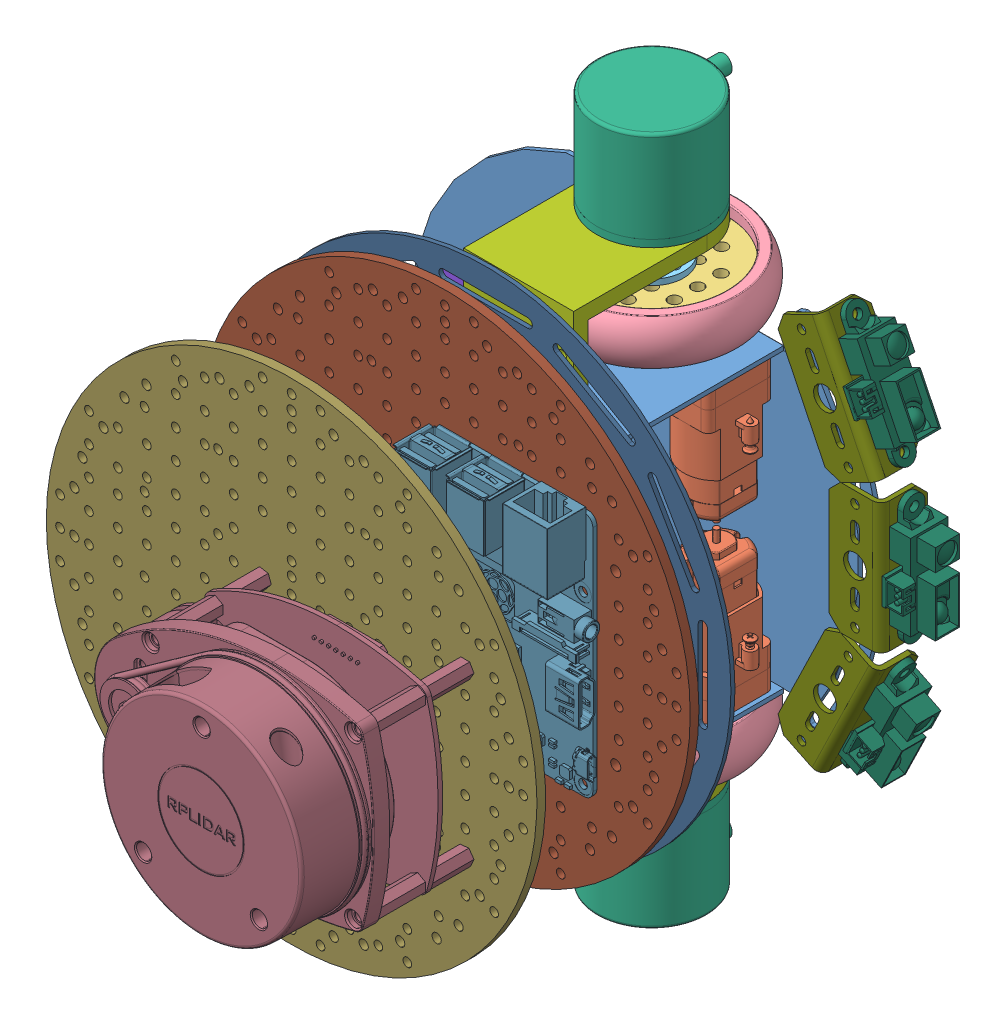
SolidWorks assembly ABOT, configuration По умолчанию. Lengths in mm.
Overall size (177.2 238 222.07).
28 component instances, 16 part files, 67 mates.
Components (placement in the parent):
- LOWER_PLATE-1: LOWER_PLATE [По умолчанию] x (0 1 0) z (1 0 0) size (144.85 55.5 162.2)
- TT_ANGLE_MOTOR_PART-1: TT_ANGLE_MOTOR_PART [По умолчанию] at (11.0834 -43.5 12.4406) x (-1 0 0) z (0 1 0) size (47.1 23 58.3)
- TT_ANGLE_MOTOR_PART-2: TT_ANGLE_MOTOR_PART [По умолчанию] at (11.0834 43.5 16.5594) x (-1 0 0) z (0 -1 0) size (47.1 23 58.3)
- MBOT_WHEEL-2: MBOT_WHEEL [Default] at (0 64 14.5) x (-0.008283 0 0.999966) z (0 -1 0) size (63.9 63.9 19.9)
  - TIMING_PULLEY_90T-1: TIMING_PULLEY_90T [Default] at origin size (57.7 57.7 16)
  - SLICK_TYRE_64x16-1: SLICK_TYRE_64x16 [Default] x (0 0 -1) z (1 0 0) size (15.8 63.9 63.9)
- MBOT_WHEEL-3: MBOT_WHEEL [Default] at (0 -64 14.5) x (0.824889 0 -0.565294) z (0 1 0) size (63.9 63.9 19.9)
  - TIMING_PULLEY_90T-1: TIMING_PULLEY_90T [Default] at origin size (57.7 57.7 16)
  - SLICK_TYRE_64x16-1: SLICK_TYRE_64x16 [Default] x (0 0 -1) z (1 0 0) size (15.8 63.9 63.9)
- 6MM_SHAFT_FLANGE-1: 6MM_SHAFT_FLANGE [Default] at (0 68 14.5) x (-0.701226 0 -0.712939) z (0 1 0) size (22 22 12)
- 6MM_SHAFT_FLANGE-2: 6MM_SHAFT_FLANGE [Default] at (0 -68 14.5) x (0.983008 0 0.183562) z (0 -1 0) size (22 22 12)
- ENCODER_LPD3806-360BM-G5-24C-1: ENCODER_LPD3806-360BM-G5-24C [Default] at (0 -119 14.5) x (-1 0 0) z (0 0 -1) size (38 51 44.01)
- PRINT_ENCODER_MOUNT-1: PRINT_ENCODER_MOUNT [По умолчанию] at (0 -85 14.5) x (0 1 0) z (1 0 0) size (46.5 65 65)
- ENCODER_LPD3806-360BM-G5-24C-2: ENCODER_LPD3806-360BM-G5-24C [Default] at (0 119 14.5) x (1 0 0) z (0 0 -1) size (38 51 44.01)
- PRINT_ENCODER_MOUNT-2: PRINT_ENCODER_MOUNT [По умолчанию] at (0 85 14.5) x (0 -1 0) z (-1 0 0) size (46.5 65 65)
- CASTER_WHEEL_CASE-1: CASTER_WHEEL_CASE [Default] at (-78 0 -10.45) x (0 1 0) z (1 0 0) size (48.4 15.95 32.2)
- CASTER_WHEEL_BALL-1: CASTER_WHEEL_BALL [Default] at (-78 0 -10.45) x (0 1 0) z (1 0 0) size (14 14 14)
- UPPER_PLATE-1: UPPER_PLATE [Default] at (-10 0 60.5) x (-1 0 0) z (0 0 1) size (169.5 169.5 1.4)
- CUT_PLEX_PLATE_0-1: CUT_PLEX_PLATE_0 [Default] at (-10 0 72.95) x (-1 0 0) z (0 0 1) size (169.5 169.5 3)
- CUT_PLEX_PLATE_1-1: CUT_PLEX_PLATE_1 [По умолчанию] at (-10 0 125.95) size (169.5 169.5 3)
- LIDAR_AXIS_FRAME-1: LIDAR_AXIS_FRAME [По умолчанию] at (22 0 183.15) size (97.49 71.78 63.21)
- RPI3-1: RPI3 [По умолчанию] at (-3.5 -31.5 86.35) size (58.5 87.6 19.8)
- GP2Y0A41SK0F_AXIS_FRAME-1: GP2Y0A41SK0F_AXIS_FRAME [По умолчанию] at (81.2 0 -6.5) x (0 -1 0) z (0 0 1) size (44.5 13.5 18.9)
- SHARP_IR_MOUNTING_BRACKET-1: SHARP_IR_MOUNTING_BRACKET [Default] at (67.7 0 3) x (-1 0 0) z (0 -1 0) size (18 16 45)
- GP2Y0A41SK0F_AXIS_FRAME-4: GP2Y0A41SK0F_AXIS_FRAME [По умолчанию] at (68.5722 54.7695 -6.5) x (0.43785 -0.899048 0) z (0 0 1) size (44.5 13.5 18.9)
- SHARP_IR_MOUNTING_BRACKET-4: SHARP_IR_MOUNTING_BRACKET [Default] at (56.435 48.8585 3) x (-0.899048 -0.43785 0) z (0.43785 -0.899048 0) size (18 16 45)
- SHARP_IR_MOUNTING_BRACKET-5: SHARP_IR_MOUNTING_BRACKET [Default] at (56.435 -48.8585 3) x (-0.899048 0.43785 0) z (-0.43785 -0.899048 0) size (18 16 45)
- GP2Y0A41SK0F_AXIS_FRAME-5: GP2Y0A41SK0F_AXIS_FRAME [По умолчанию] at (68.5722 -54.7695 -6.5) x (-0.43785 -0.899048 0) z (0 0 1) size (44.5 13.5 18.9)
Mates (geometry in assembly coordinates):
- Концентричный1: concentric aligned: cylinder of LOWER_PLATE-1 through (0 54 14.5) axis (0 -1 0) radius 4; cylinder of TT_ANGLE_MOTOR_PART-2 through (0 59.3 14.5) axis (0 -1 0) radius 2.7
- Параллельность1: parallel anti-aligned: plane of LOWER_PLATE-1 through (0 0 1.5) normal (0 0 1); plane of TT_ANGLE_MOTOR_PART-2 through (28.5 50.5 3) normal (0 0 -1)
- Совпадение2: coincident anti-aligned: plane of LOWER_PLATE-1 through (-32.5 50.5 55) normal (0 -1 0); plane of TT_ANGLE_MOTOR_PART-2 through (-8.5 50.5 5.5) normal (0 1 0)
- Концентричный2: concentric anti-aligned: cylinder of LOWER_PLATE-1 through (0 54 14.5) axis (0 -1 0) radius 4; cylinder of TT_ANGLE_MOTOR_PART-1 through (0 -59.3 14.5) axis (0 1 0) radius 2.7
- Параллельность2: parallel aligned: plane of LOWER_PLATE-1 through (0 0 1.5) normal (0 0 1); plane of TT_ANGLE_MOTOR_PART-1 through (28.5 -50.5 26) normal (0 0 1)
- Совпадение4: coincident anti-aligned: plane of LOWER_PLATE-1 through (-32.5 -50.5 55) normal (0 1 0); plane of TT_ANGLE_MOTOR_PART-1 through (-8.5 -50.5 23.5) normal (0 -1 0)
- Концентричный3: concentric anti-aligned: cylinder of TT_ANGLE_MOTOR_PART-2 through (0 59.3 14.5) axis (0 -1 0) radius 2.7; cylinder of MBOT_WHEEL-2/TIMING_PULLEY_90T-1 through (0 52 14.5) axis (0 1 0) radius 5
- Концентричный4: concentric anti-aligned: cylinder of TT_ANGLE_MOTOR_PART-1 through (0 -59.3 14.5) axis (0 1 0) radius 2.7; cylinder of MBOT_WHEEL-3/TIMING_PULLEY_90T-1 through (0 -52 14.5) axis (0 -1 0) radius 5
- Совпадение5: coincident anti-aligned: plane of LOWER_PLATE-1 through (0 -52 55) normal (0 -1 0); plane of MBOT_WHEEL-3/TIMING_PULLEY_90T-1 through (0 -52 14.5) normal (0 1 0)
- Совпадение6: coincident anti-aligned: plane of LOWER_PLATE-1 through (0 52 55) normal (0 1 0); plane of MBOT_WHEEL-2/TIMING_PULLEY_90T-1 through (0 52 14.5) normal (0 -1 0)
- Концентричный5: concentric anti-aligned: cylinder of MBOT_WHEEL-2/TIMING_PULLEY_90T-1 through (0 64 14.5) axis (0 1 0) radius 4; cylinder of 6MM_SHAFT_FLANGE-1 through (0 80 14.5) axis (0 -1 0) radius 3
- Концентричный6: concentric anti-aligned: cylinder of MBOT_WHEEL-2/TIMING_PULLEY_90T-1 through (0.0663 68 6.5003) axis (0 -1 0) radius 2.05; cylinder of 6MM_SHAFT_FLANGE-1 through (0.0663 60 6.5003) axis (0 1 0) radius 1.5
- Совпадение7: coincident anti-aligned: plane of MBOT_WHEEL-2/TIMING_PULLEY_90T-1 through (0 68 14.5) normal (0 1 0); plane of 6MM_SHAFT_FLANGE-1 through (0 68 14.5) normal (0 -1 0)
- Концентричный7: concentric anti-aligned: cylinder of MBOT_WHEEL-3/TIMING_PULLEY_90T-1 through (0 -64 14.5) axis (0 -1 0) radius 4; cylinder of 6MM_SHAFT_FLANGE-2 through (0 -80 14.5) axis (0 1 0) radius 3
- Концентричный10: concentric anti-aligned: cylinder of MBOT_WHEEL-3/TIMING_PULLEY_90T-1 through (6.5991 -68 9.9776) axis (0 1 0) radius 2.05; cylinder of 6MM_SHAFT_FLANGE-2 through (6.5991 -60 9.9776) axis (0 -1 0) radius 1.5
- Совпадение8: coincident anti-aligned: plane of MBOT_WHEEL-3/TIMING_PULLEY_90T-1 through (0 -68 14.5) normal (0 -1 0); plane of 6MM_SHAFT_FLANGE-2 through (0 -68 14.5) normal (0 1 0)
- Концентричный11: concentric anti-aligned: cylinder of ENCODER_LPD3806-360BM-G5-24C-1 through (0 -80 14.5) axis (0 -1 0) radius 10; cylinder of PRINT_ENCODER_MOUNT-1 through (0 -99 14.5) axis (0 1 0) radius 10
- Концентричный12: concentric aligned: cylinder of ENCODER_LPD3806-360BM-G5-24C-1 through (0 -92 28.5) axis (0 1 0) radius 1.5; cylinder of PRINT_ENCODER_MOUNT-1 through (0 -85 28.5) axis (0 1 0) radius 1.5
- Совпадение9: coincident anti-aligned: plane of ENCODER_LPD3806-360BM-G5-24C-1 through (0 -85 14.5) normal (0 1 0); plane of PRINT_ENCODER_MOUNT-1 through (-32.5 -85 14.5) normal (0 -1 0)
- Концентричный13: concentric anti-aligned: cylinder of 6MM_SHAFT_FLANGE-2 through (0 -80 14.5) axis (0 1 0) radius 3; cylinder of ENCODER_LPD3806-360BM-G5-24C-1 through (0 -68 14.5) axis (0 -1 0) radius 3
- Совпадение10: coincident anti-aligned: plane of 6MM_SHAFT_FLANGE-2 through (0 -80 14.5) normal (0 -1 0); plane of ENCODER_LPD3806-360BM-G5-24C-1 through (0 -80 14.5) normal (0 1 0)
- Параллельность4: parallel anti-aligned: plane of PRINT_ENCODER_MOUNT-1 through (-32.5 -85 55.5) normal (0 0 -1); plane of LOWER_PLATE-1 through (0 0 1.5) normal (0 0 1)
- Совпадение12: coincident anti-aligned: plane of ENCODER_LPD3806-360BM-G5-24C-2 through (0 85 14.5) normal (0 -1 0); plane of PRINT_ENCODER_MOUNT-2 through (32.5 85 14.5) normal (0 1 0)
- Концентричный14: concentric aligned: cylinder of ENCODER_LPD3806-360BM-G5-24C-2 through (0 92 28.5) axis (0 -1 0) radius 1.5; cylinder of PRINT_ENCODER_MOUNT-2 through (0 85 28.5) axis (0 -1 0) radius 1.5
- Концентричный15: concentric anti-aligned: cylinder of ENCODER_LPD3806-360BM-G5-24C-2 through (0 80 14.5) axis (0 1 0) radius 10; cylinder of PRINT_ENCODER_MOUNT-2 through (0 99 14.5) axis (0 -1 0) radius 10
- Концентричный16: concentric anti-aligned: cylinder of 6MM_SHAFT_FLANGE-1 through (0 80 14.5) axis (0 -1 0) radius 3; cylinder of ENCODER_LPD3806-360BM-G5-24C-2 through (0 68 14.5) axis (0 1 0) radius 3
- Параллельность5: parallel aligned: plane of PRINT_ENCODER_MOUNT-2 through (32.5 85 60.5) normal (0 0 1); plane of LOWER_PLATE-1 through (0 0 1.5) normal (0 0 1)
- Совпадение14: coincident anti-aligned: plane of 6MM_SHAFT_FLANGE-1 through (0 80 14.5) normal (0 1 0); plane of ENCODER_LPD3806-360BM-G5-24C-2 through (0 80 14.5) normal (0 -1 0)
- Концентричный17: concentric anti-aligned: cylinder of LOWER_PLATE-1 through (-78 0 1.5) axis (0 0 -1) radius 16; cylinder of CASTER_WHEEL_CASE-1 through (-78 0 -13.45) axis (0 0 1) radius 16.1
- Концентричный18: concentric aligned: cylinder of LOWER_PLATE-1 through (-78 20 0) axis (0 0 1) radius 2.05; cylinder of CASTER_WHEEL_CASE-1 through (-78 20 -13.45) axis (0 0 1) radius 2
- Совпадение15: coincident anti-aligned: plane of LOWER_PLATE-1 through (0 0 1.5) normal (0 0 1); plane of CASTER_WHEEL_CASE-1 through (-78 0 1.5) normal (0 0 -1)
- Совпадение16: coordinate: point of CASTER_WHEEL_CASE-1; point of CASTER_WHEEL_BALL-1
- Концентричный22: concentric aligned: cylinder of LOWER_PLATE-1 through (25 -45 55.5) axis (0 0 -1) radius 1.5; cylinder of UPPER_PLATE-1 through (25 -45 61.9) axis (0 0 -1) radius 2
- Концентричный23: concentric aligned: cylinder of LOWER_PLATE-1 through (-25 45 55.5) axis (0 0 -1) radius 1.5; cylinder of UPPER_PLATE-1 through (-25 45 61.9) axis (0 0 -1) radius 2
- Совпадение17: coincident anti-aligned: plane of PRINT_ENCODER_MOUNT-2 through (32.5 85 60.5) normal (0 0 1); plane of UPPER_PLATE-1 through (-10 0 60.5) normal (0 0 -1)
- Концентричный26: concentric aligned: cylinder of UPPER_PLATE-1 through (-10 0 61.9) axis (0 0 -1) radius 84.75; cylinder of CUT_PLEX_PLATE_0-1 through (-10 0 75.95) axis (0 0 -1) radius 84.75
- Расстояние2: distance = 11.05 mm anti-aligned: plane of CUT_PLEX_PLATE_0-1 through (-10 0 72.95) normal (0 0 -1); plane of UPPER_PLATE-1 through (-10 0 61.9) normal (0 0 1)
- Концентричный29: concentric aligned: cylinder of CUT_PLEX_PLATE_1-1 through (50 28 128.95) axis (0 0 -1) radius 1.5; cylinder of LIDAR_AXIS_FRAME-1 through (50 28 162.15) axis (0 0 -1) radius 1.5
- Концентричный30: concentric aligned: cylinder of CUT_PLEX_PLATE_1-1 through (50 -28 128.95) axis (0 0 -1) radius 1.5; cylinder of LIDAR_AXIS_FRAME-1 through (50 -28 143.75) axis (0 0 -1) radius 1.5
- Совпадение21: coincident anti-aligned: plane of CUT_PLEX_PLATE_1-1 through (-10 0 128.95) normal (0 0 1); plane of LIDAR_AXIS_FRAME-1 through (50 -28 128.95) normal (0 0 -1)
- Концентричный31: concentric aligned: cylinder of CUT_PLEX_PLATE_0-1 through (-10 0 75.95) axis (0 0 -1) radius 84.75; cylinder of CUT_PLEX_PLATE_1-1 through (-10 0 128.95) axis (0 0 -1) radius 84.75
- Расстояние3: distance = 50 mm anti-aligned: plane of CUT_PLEX_PLATE_0-1 through (-10 0 75.95) normal (0 0 1); plane of CUT_PLEX_PLATE_1-1 through (-10 0 125.95) normal (0 0 -1)
- Концентричный33: concentric anti-aligned: cylinder of CUT_PLEX_PLATE_0-1 through (0 -28 75.95) axis (0 0 -1) radius 1.75; cylinder of RPI3-1 through (0 -28 87.35) axis (0 0 1) radius 1.5
- Параллельность10: parallel anti-aligned: plane of UPPER_PLATE-1 through (-83.45 14.55 60.5) normal (-1 0 0); plane of RPI3-1 through (50.1 45.4409 87.35) normal (1 0 0)
- Расстояние4: distance = 10 mm anti-aligned: plane of RPI3-1 through (-3.5 -31.5 85.95) normal (0 0 -1); plane of CUT_PLEX_PLATE_0-1 through (-10 0 75.95) normal (0 0 1)
- Концентричный34: concentric anti-aligned: cylinder of UPPER_PLATE-1 through (-85.05 14.55 60.5) axis (0 0 1) radius 1.6; cylinder of CUT_PLEX_PLATE_0-1 through (-85.05 14.55 75.95) axis (0 0 -1) radius 1.6
- Концентричный35: concentric anti-aligned: cylinder of UPPER_PLATE-1 through (-85.05 -14.55 60.5) axis (0 0 1) radius 1.6; cylinder of CUT_PLEX_PLATE_0-1 through (-85.05 -14.55 75.95) axis (0 0 -1) radius 1.6
- Концентричный36: concentric aligned: cylinder of CUT_PLEX_PLATE_0-1 through (-90 0 75.95) axis (0 0 -1) radius 1.5; cylinder of CUT_PLEX_PLATE_1-1 through (-90 0 128.95) axis (0 0 -1) radius 1.5
- Концентричный38: concentric anti-aligned: cylinder of GP2Y0A41SK0F_AXIS_FRAME-1 through (72.7 -18.5 -6.5) axis (-1 0 0) radius 1.6; cylinder of SHARP_IR_MOUNTING_BRACKET-1 through (49.7 -18.5 -6.5) axis (1 0 0) radius 1.5
- Совпадение23: coincident anti-aligned: plane of GP2Y0A41SK0F_AXIS_FRAME-1 through (67.7 0 -6.5) normal (-1 0 0); plane of SHARP_IR_MOUNTING_BRACKET-1 through (67.7 -22.5 3) normal (1 0 0)
- Концентричный39: concentric anti-aligned: cylinder of GP2Y0A41SK0F_AXIS_FRAME-1 through (72.7 18.5 -6.5) axis (-1 0 0) radius 1.6; cylinder of SHARP_IR_MOUNTING_BRACKET-1 through (49.7 18.5 -6.5) axis (1 0 0) radius 1.5
- Касательность1: tangent anti-aligned: cylinder of LOWER_PLATE-1 through (-35.8 0 1.5) axis (0 0 -1) radius 102; plane of SHARP_IR_MOUNTING_BRACKET-1 through (66.2 -22.5 -13) normal (-1 0 0)
- Совпадение24: coincident anti-aligned: plane of LOWER_PLATE-1 through (0 0 1.5) normal (0 0 1); plane of SHARP_IR_MOUNTING_BRACKET-1 through (49.7 -22.5 1.5) normal (0 0 -1)
- Параллельность11: parallel aligned: plane of SHARP_IR_MOUNTING_BRACKET-1 through (67.7 -22.5 3) normal (1 0 0); plane of assembly through (0 0 0) normal (1 0 0)
- Совпадение26: coincident: point of GP2Y0A41SK0F_AXIS_FRAME-1; plane of assembly
- Концентричный40: concentric anti-aligned: cylinder of GP2Y0A41SK0F_AXIS_FRAME-4 through (69.0305 34.4154 -6.5) axis (-0.899048 -0.43785 0) radius 1.6; cylinder of SHARP_IR_MOUNTING_BRACKET-4 through (48.3524 24.3448 -6.5) axis (0.899048 0.43785 0) radius 1.5
- Совпадение27: coincident anti-aligned: plane of GP2Y0A41SK0F_AXIS_FRAME-4 through (56.435 48.8585 -6.5) normal (-0.899048 -0.43785 0); plane of SHARP_IR_MOUNTING_BRACKET-4 through (66.2867 28.6299 3) normal (0.899048 0.43785 0)
- Концентричный41: concentric anti-aligned: cylinder of GP2Y0A41SK0F_AXIS_FRAME-4 through (52.83 67.6801 -6.5) axis (-0.899048 -0.43785 0) radius 1.6; cylinder of SHARP_IR_MOUNTING_BRACKET-4 through (32.1519 57.6096 -6.5) axis (0.899048 0.43785 0) radius 1.5
- Совпадение28: coincident anti-aligned: plane of LOWER_PLATE-1 through (0 0 1.5) normal (0 0 1); plane of SHARP_IR_MOUNTING_BRACKET-4 through (50.1038 20.7486 1.5) normal (0 0 -1)
- Совпадение30: coincident anti-aligned: line of SHARP_IR_MOUNTING_BRACKET-1 through (53.7 22.5 1.5) axis (0 0 1); line of SHARP_IR_MOUNTING_BRACKET-4 through (53.7 22.5 3) axis (0 0 -1)
- Расстояние5: distance = 2.8 mm: line of LOWER_PLATE-1 through (32.5 50.5 54) axis (0 0 -1); plane of SHARP_IR_MOUNTING_BRACKET-4 through (50.1038 20.7486 3) normal (-0.899048 -0.43785 0)
- Концентричный42: concentric anti-aligned: cylinder of SHARP_IR_MOUNTING_BRACKET-5 through (32.1519 -57.6096 -6.5) axis (0.899048 -0.43785 0) radius 1.5; cylinder of GP2Y0A41SK0F_AXIS_FRAME-5 through (52.83 -67.6801 -6.5) axis (-0.899048 0.43785 0) radius 1.6
- Концентричный43: concentric anti-aligned: cylinder of SHARP_IR_MOUNTING_BRACKET-5 through (48.3524 -24.3448 -6.5) axis (0.899048 -0.43785 0) radius 1.5; cylinder of GP2Y0A41SK0F_AXIS_FRAME-5 through (69.0305 -34.4154 -6.5) axis (-0.899048 0.43785 0) radius 1.6
- Совпадение33: coincident anti-aligned: plane of SHARP_IR_MOUNTING_BRACKET-5 through (46.5834 -69.0871 3) normal (0.899048 -0.43785 0); plane of GP2Y0A41SK0F_AXIS_FRAME-5 through (56.435 -48.8585 -6.5) normal (-0.899048 0.43785 0)
- Совпадение34: coincident anti-aligned: plane of LOWER_PLATE-1 through (0 0 1.5) normal (0 0 1); plane of SHARP_IR_MOUNTING_BRACKET-5 through (30.4005 -61.2057 1.5) normal (0 0 -1)
- Совпадение35: coincident anti-aligned: line of SHARP_IR_MOUNTING_BRACKET-1 through (53.7 -22.5 3) axis (0 0 -1); line of SHARP_IR_MOUNTING_BRACKET-5 through (53.7 -22.5 1.5) axis (0 0 1)
- Расстояние6: distance = 2.8 mm: line of LOWER_PLATE-1 through (32.5 -50.5 54) axis (0 0 -1); plane of SHARP_IR_MOUNTING_BRACKET-5 through (30.4005 -61.2057 3) normal (-0.899048 0.43785 0)
